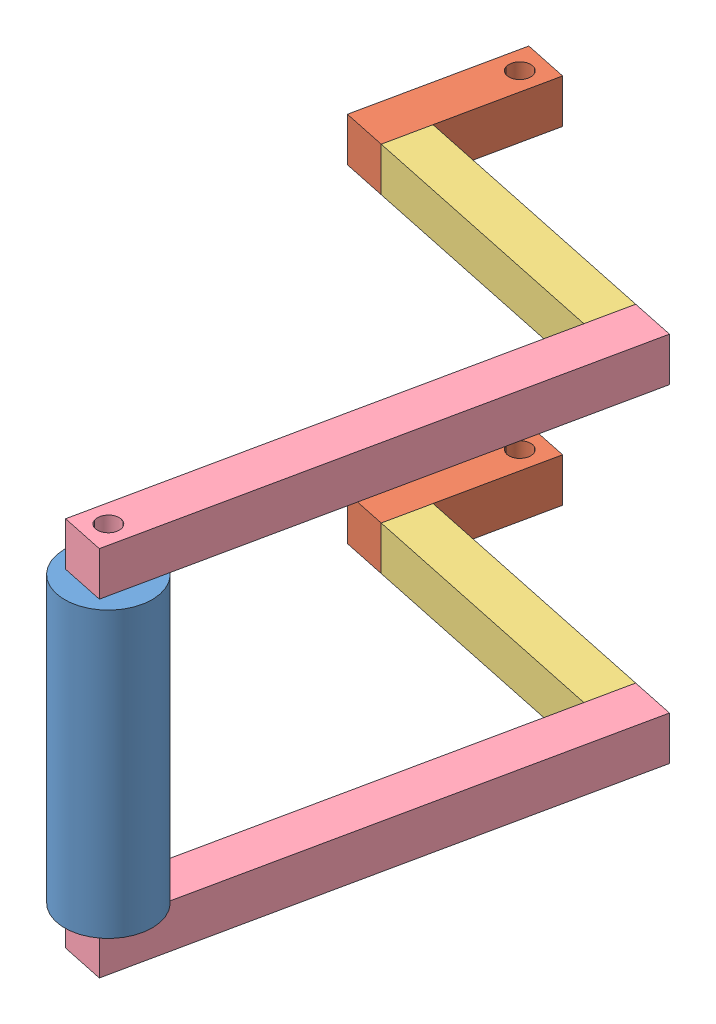
SolidWorks assembly scoring mech v2, configuration Default. Lengths in mm.
Overall size (204.07 215.9 398.25).
7 component instances, 4 part files, 15 mates.
Components (placement in the parent):
- intake rollers-2: intake rollers [Default] at (294.5874 283.4141 486.6007) x (0.660065 0 -0.751209) z (0.751209 0 0.660065) size (50.8 165.1 50.8)
- roller holder-2: roller holder [Default] at (185.8135 258.0141 202.2775) x (0.206339 0 -0.978481) z (0.978481 0 0.206339) size (88.9 25.4 25.4)
- roller part 1-1: roller part 1 [Default] at (188.0707 258.0141 191.5735) x (0.978481 0 0.206339) z (-0.206339 0 0.978481) size (152.4 25.4 25.4)
- roller part 1-4: roller part 1 [Default] at (188.0707 448.5141 191.5735) x (0.978481 0 0.206339) z (-0.206339 0 0.978481) size (152.4 25.4 25.4)
- roller holder-5: roller holder [Default] at (185.8135 448.5141 202.2775) x (0.206339 0 -0.978481) z (0.978481 0 0.206339) size (88.9 25.4 25.4)
- roller part 2 holes-2: roller part 2 holes [Default] at (362.0446 448.5141 228.2605) x (0.978481 0 0.206339) z (-0.206339 0 0.978481) size (25.4 25.4 279.4)
- roller part 2 holes-4: roller part 2 holes [Default] at (362.0446 258.0141 228.2605) x (0.978481 0 0.206339) z (-0.206339 0 0.978481) size (25.4 25.4 279.4)
Mates (geometry in assembly coordinates):
- Coincident28: coincident aligned: plane of roller holder-2 through (185.8135 283.4141 202.2775) normal (0 1 0); plane of roller part 1-1 through (337.1912 283.4141 223.0195) normal (0 1 0)
- Coincident29: coincident anti-aligned: plane of roller holder-2 through (182.8297 283.4141 216.4269) normal (0.978481 0 0.206339); plane of roller part 1-1 through (188.0707 258.0141 191.5735) normal (-0.978481 0 -0.206339)
- Coincident30: coincident aligned: plane of roller holder-2 through (182.8297 283.4141 216.4269) normal (-0.206339 0 0.978481); plane of roller part 1-1 through (331.9502 258.0141 247.8729) normal (-0.206339 0 0.978481)
- Coincident55: coincident aligned: plane of roller part 1-4 through (337.1912 473.9141 223.0195) normal (0 1 0); plane of roller holder-5 through (185.8135 473.9141 202.2775) normal (0 1 0)
- Coincident56: coincident anti-aligned: plane of roller part 1-4 through (188.0707 448.5141 191.5735) normal (-0.978481 0 -0.206339); plane of roller holder-5 through (182.8297 473.9141 216.4269) normal (0.978481 0 0.206339)
- Coincident60: coincident aligned: plane of roller part 1-4 through (331.9502 448.5141 247.8729) normal (-0.206339 0 0.978481); plane of roller holder-5 through (182.8297 473.9141 216.4269) normal (-0.206339 0 0.978481)
- Coincident69: coincident anti-aligned: plane of roller part 1-4 through (337.1912 448.5141 223.0195) normal (0.978481 0 0.206339); plane of roller part 2 holes-2 through (279.5402 448.5141 496.407) normal (-0.978481 0 -0.206339)
- Coincident70: coincident aligned: plane of roller part 1-4 through (337.1912 473.9141 223.0195) normal (0 1 0); plane of roller part 2 holes-2 through (304.3936 473.9141 501.6479) normal (0 1 0)
- Coincident71: coincident aligned: plane of roller part 1-4 through (337.1912 448.5141 223.0195) normal (0.206339 0 -0.978481); plane of roller part 2 holes-2 through (362.0446 448.5141 228.2605) normal (0.206339 0 -0.978481)
- Coincident72: coincident aligned: circle of intake rollers-2; circle of roller part 2 holes-2
- Coincident77: coincident anti-aligned: plane of roller part 1-1 through (337.1912 258.0141 223.0195) normal (0.978481 0 0.206339); plane of roller part 2 holes-4 through (279.5402 258.0141 496.407) normal (-0.978481 0 -0.206339)
- Coincident78: coincident aligned: plane of roller part 1-1 through (337.1912 258.0141 223.0195) normal (0.206339 0 -0.978481); plane of roller part 2 holes-4 through (362.0446 258.0141 228.2605) normal (0.206339 0 -0.978481)
- Coincident79: coincident aligned: plane of roller part 1-1 through (337.1912 283.4141 223.0195) normal (0 1 0); plane of roller part 2 holes-4 through (304.3936 283.4141 501.6479) normal (0 1 0)
- Coincident81: coincident aligned: circle of intake rollers-2; circle of roller part 2 holes-4
- Concentric4: concentric aligned: cylinder of roller holder-2 through (186.126 283.4141 139.2461) axis (0 -1 0) radius 6.35; cylinder of roller holder-5 through (186.126 473.9141 139.2461) axis (0 -1 0) radius 6.35
